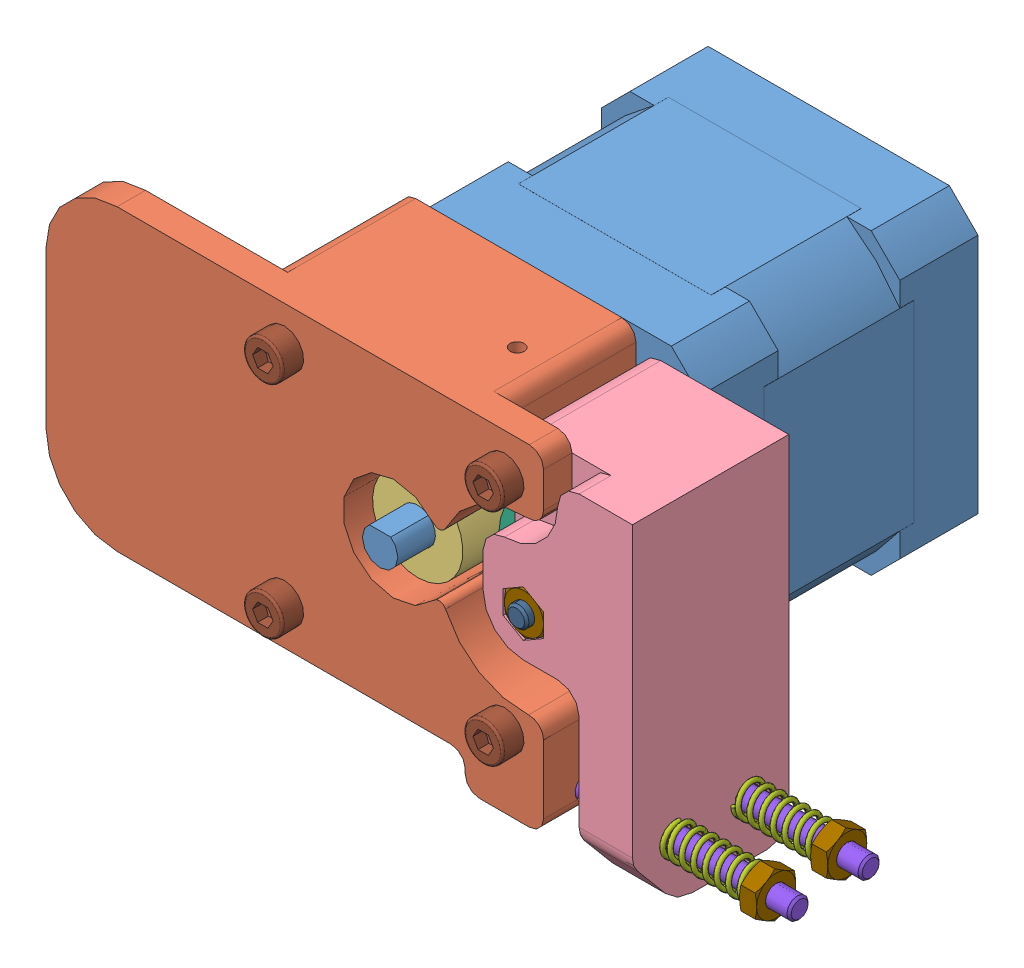
SolidWorks assembly filament drive, configuration Default. Lengths in mm.
Overall size (100 51.55 64.12).
18 component instances, 11 part files, 0 mates.
Components (placement in the parent):
- _STEPPER-1: _STEPPER [Default] at origin size (42.02 42.02 63.12)
- block-1: block [Default] at (0 0 50.116) x (1 0 0) z (0 0 -1) size (70 46.6 22)
- HOBBED PULLEY-1: HOBBED PULLEY [Default] at (-0.0119 0.0005 47.017) x (0.986795 -0.161973 0) z (0 0 1) size (12.7 12.7 10.79)
- ARM-1: ARM [Default] at (0 0 39.116) size (21 49.04 22)
- BEARING INSERT-1: BEARING INSERT [Default] at (18.1475 0 53.616) x (0.992272 -0.124084 0) z (0 0 -1) size (7.8 7.8 7)
- _608-1: _608 [Default] at (18.1475 0 46.616) x (0.992272 -0.124084 0) z (0 0 1) size (22 22 7)
- SPRING-1: SPRING [Default] at (46.8346 -22.6 55.0956) x (0 0.121202 0.992628) z (-1 0 0) size (5.11 5.12 13.44)
- SPRING-2: SPRING [Default] at (46.8346 -22.6 45.0956) x (0 -0.999883 -0.015292) z (-1 0 0) size (5.11 5.12 13.44)
- M3x35-1: M3x35 [Default] at (16 -22.6 55.0956) size (38 5.5 5.5)
- M3x35-2: M3x35 [Default] at (16 -22.6 45.0956) size (38 5.5 5.5)
- M3 NUT-1: M3 NUT [Default] at (45.3 -22.6 45.0956) size (2.4 6.35 5.5)
- M3 NUT-2: M3 NUT [Default] at (45.3 -22.6 55.0956) size (2.4 6.35 5.5)
- M3 NUT-3: M3 NUT [Default] at (18.1475 0 61.016) x (0 0 -1) z (1 0 0) size (2.4 6.35 5.5)
- M3x20-1: M3x20 [Default] at (18.1475 0 42.116) x (0 0 1) z (-0.990926 0.134409 0) size (23 5.5 5.5)
- M3x25-1: M3x25 [Default] at (15.5 -15.5 61.116) x (0 0 -1) z (1 0 0) size (28 5.5 5.5)
- M3x25-2: M3x25 [Default] at (-15.5 -15.5 61.116) x (0 0 -1) z (1 0 0) size (28 5.5 5.5)
- M3x25-3: M3x25 [Default] at (-15.5 15.5 61.116) x (0 0 -1) z (1 0 0) size (28 5.5 5.5)
- M3x25-4: M3x25 [Default] at (15.5 15.5 61.116) x (0 0 -1) z (1 0 0) size (28 5.5 5.5)
